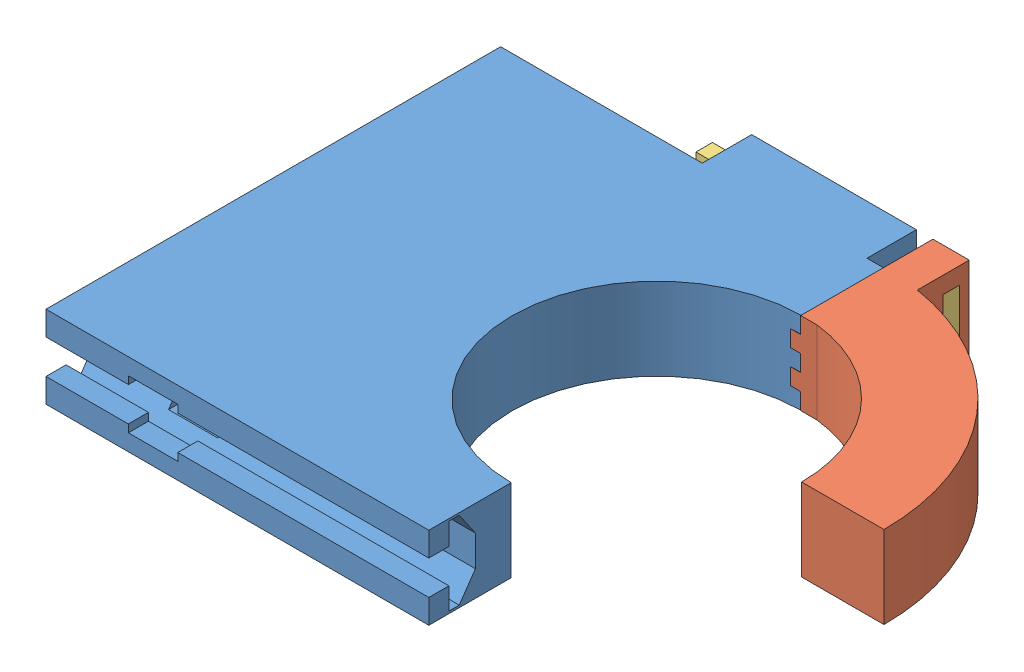
SolidWorks assembly Mouse House Holder Assembly, configuration Default. Lengths in mm.
Overall size (94.03 12.7 77.74).
3 component instances, 3 part files, 5 mates.
Components (placement in the parent):
- Mouse House Holder-1: Mouse House Holder [Default] at (65.2284 40.1827 39.2967) size (59.03 12.7 77.72)
- Mouse House Holer Slide-1: Mouse House Holer Slide [Default] at (65.112 40.1827 39.1617) x (0 0 -1) z (0 1 0) size (42.55 37.54 12.7)
- Mouse House Holder Slide Lock-1: Mouse House Holder Slide Lock [Default] at (70.7063 46.4791 -0.622) x (0 -1 0) z (-1 0 0) size (7.62 5.08 38.1)
Mates (geometry in assembly coordinates):
- Coincident1: coincident anti-aligned: plane of Mouse House Holder-1 through (65.112 40.1827 76.761) normal (1 0 0); plane of Mouse House Holer Slide-1 through (65.112 40.1827 39.1617) normal (-1 0 0)
- Coincident3: coincident aligned: plane of Mouse House Holder-1 through (65.2284 52.8827 39.2967) normal (0 1 0); plane of Mouse House Holer Slide-1 through (65.112 52.8827 39.1617) normal (0 1 0)
- Coincident7: coincident aligned: plane of Mouse House Holer Slide-1 through (70.7063 52.8827 -3.3889) normal (1 0 0); plane of Mouse House Holder Slide Lock-1 through (70.7063 46.4791 -0.622) normal (1 0 0)
- Parallel2: parallel aligned: plane of Mouse House Holer Slide-1 through (65.112 40.1827 39.1617) normal (0 -1 0); plane of Mouse House Holder Slide Lock-1 through (70.7063 42.6691 -0.622) normal (0 -1 0)
- Parallel3: parallel aligned: plane of Mouse House Holer Slide-1 through (65.112 52.8827 39.1617) normal (0 1 0); plane of Mouse House Holder Slide Lock-1 through (70.7063 50.2891 -0.622) normal (0 1 0)
